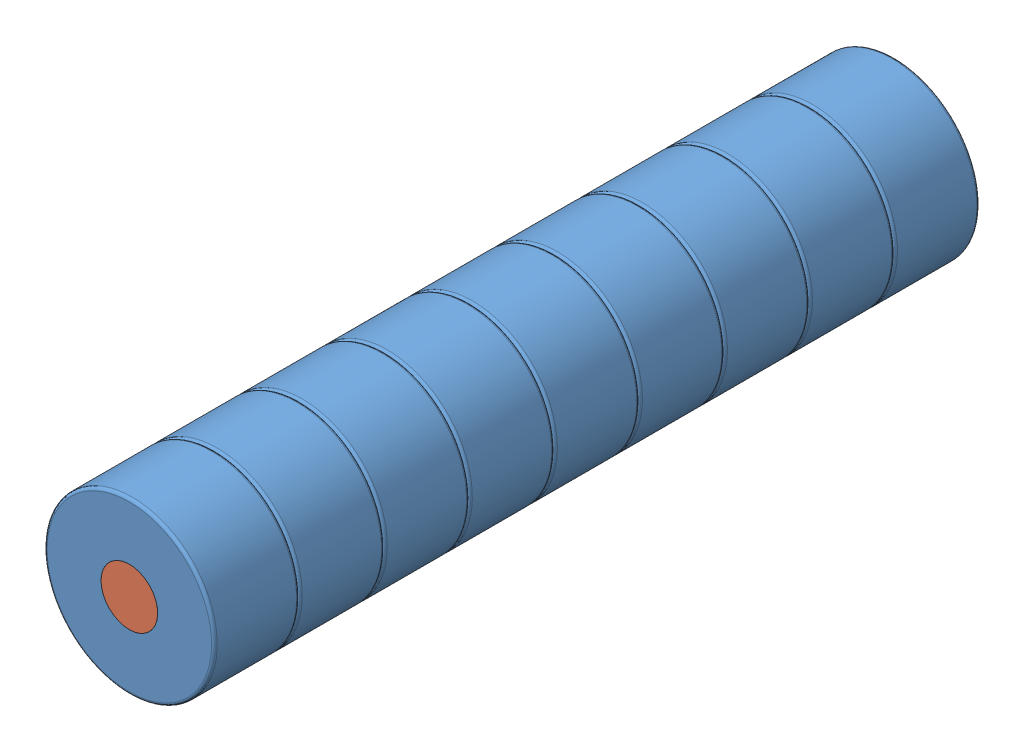
SolidWorks assembly longbearings, configuration Default. Lengths in mm.
Overall size (7.97 7.97 27).
10 component instances, 2 part files, 18 mates.
Components (placement in the parent):
- ballbearing-1: ballbearing [Default] at (2.4595 4.6245 26.9322) x (0 0 1) z (-0.933919 -0.357485 0) size (3 6 6)
- ballbearing-2: ballbearing [Default] at (2.4595 4.6245 2.9322) x (0 0 1) z (-0.999686 0.025064 0) size (3 6 6)
- ballbearing-3: ballbearing [Default] at (2.4595 4.6245 11.9322) x (0 0 1) z (-0.999512 -0.031225 0) size (3 6 6)
- ballbearing-4: ballbearing [Default] at (2.4595 4.6245 23.9322) x (0 0 1) z (-0.99915 -0.041216 0) size (3 6 6)
- ballbearing-5: ballbearing [Default] at (2.4595 4.6245 5.9322) x (0 0 1) z (-0.99915 -0.041216 0) size (3 6 6)
- ballbearing-6: ballbearing [Default] at (2.4595 4.6245 14.9322) x (0 0 1) z (-0.99915 -0.041216 0) size (3 6 6)
- ballbearing-7: ballbearing [Default] at (2.4595 4.6245 8.9322) x (0 0 1) z (-0.99915 -0.041216 0) size (3 6 6)
- ballbearing-8: ballbearing [Default] at (2.4595 4.6245 17.9322) x (0 0 1) z (-0.218913 -0.975744 0) size (3 6 6)
- ballbearing-9: ballbearing [Default] at (2.4595 4.6245 20.9322) x (0 0 1) z (-0.420647 -0.907224 0) size (3 6 6)
- Copy of Copy of Part3^longbearings-1: Copy of Copy of Part3^longbearings [Default] at (-18.2189 -27.0895 2.9322) size (2 2 27) (virtual)
Mates (geometry in assembly coordinates):
- Coincident8: coincident aligned: plane of ballbearing-1 through (2.4595 4.6245 29.9322) normal (0 0 1); plane of Copy of Copy of Part3^Assem1-1 through (2.4595 4.6245 29.9322) normal (0 0 1)
- Concentric3: concentric aligned: cylinder of ballbearing-1 through (2.4595 4.6245 29.9322) axis (0 0 -1) radius 1; cylinder of Copy of Copy of Part3^Assem1-1 through (2.4595 4.6245 29.9322) axis (0 0 -1) radius 1
- Concentric5: concentric aligned: cylinder of ballbearing-3 through (2.4595 4.6245 14.9322) axis (0 0 -1) radius 1; cylinder of Copy of Copy of Part3^Assem1-1 through (2.4595 4.6245 29.9322) axis (0 0 -1) radius 1
- Concentric6: concentric aligned: cylinder of Copy of Copy of Part3^spaced3bearing-1 through (2.4595 4.6245 29.9322) axis (0 0 -1) radius 1; cylinder of ballbearing-4 through (2.4595 4.6245 26.9322) axis (0 0 -1) radius 1
- Coincident9: coincident anti-aligned: plane of ballbearing-1 through (2.4595 4.6245 26.9322) normal (0 0 -1); plane of ballbearing-4 through (2.4595 4.6245 26.9322) normal (0 0 1)
- Concentric7: concentric aligned: cylinder of Copy of Copy of Part3^spaced3bearing-1 through (2.4595 4.6245 29.9322) axis (0 0 -1) radius 1; cylinder of ballbearing-5 through (2.4595 4.6245 8.9322) axis (0 0 -1) radius 1
- Coincident10: coincident anti-aligned: plane of ballbearing-2 through (2.4595 4.6245 5.9322) normal (0 0 1); plane of ballbearing-5 through (2.4595 4.6245 5.9322) normal (0 0 -1)
- Coincident11: coincident aligned: plane of ballbearing-2 through (2.4595 4.6245 2.9322) normal (0 0 -1); plane of Copy of Copy of Part3^spaced3bearing-1 through (2.4595 4.6245 2.9322) normal (0 0 -1)
- Concentric8: concentric aligned: cylinder of ballbearing-2 through (2.4595 4.6245 5.9322) axis (0 0 -1) radius 1; cylinder of Copy of Copy of Part3^spaced3bearing-1 through (2.4595 4.6245 29.9322) axis (0 0 -1) radius 1
- Concentric9: concentric aligned: cylinder of Copy of Copy of Part3^spaced3bearing-1 through (2.4595 4.6245 29.9322) axis (0 0 -1) radius 1; cylinder of ballbearing-6 through (2.4595 4.6245 17.9322) axis (0 0 -1) radius 1
- Coincident12: coincident anti-aligned: plane of ballbearing-3 through (2.4595 4.6245 14.9322) normal (0 0 1); plane of ballbearing-6 through (2.4595 4.6245 14.9322) normal (0 0 -1)
- Concentric10: concentric aligned: cylinder of Copy of Copy of Part3^spaced3bearing-1 through (2.4595 4.6245 29.9322) axis (0 0 -1) radius 1; cylinder of ballbearing-7 through (2.4595 4.6245 11.9322) axis (0 0 -1) radius 1
- Coincident13: coincident anti-aligned: plane of ballbearing-5 through (2.4595 4.6245 8.9322) normal (0 0 1); plane of ballbearing-7 through (2.4595 4.6245 8.9322) normal (0 0 -1)
- Coincident14: coincident anti-aligned: plane of ballbearing-3 through (2.4595 4.6245 11.9322) normal (0 0 -1); plane of ballbearing-7 through (2.4595 4.6245 11.9322) normal (0 0 1)
- Concentric11: concentric aligned: cylinder of Copy of Copy of Part3^spaced3bearing-1 through (2.4595 4.6245 29.9322) axis (0 0 -1) radius 1; cylinder of ballbearing-8 through (2.4595 4.6245 20.9322) axis (0 0 -1) radius 1
- Coincident15: coincident anti-aligned: plane of ballbearing-6 through (2.4595 4.6245 17.9322) normal (0 0 1); plane of ballbearing-8 through (2.4595 4.6245 17.9322) normal (0 0 -1)
- Concentric12: concentric aligned: cylinder of ballbearing-9 through (2.4595 4.6245 23.9322) axis (0 0 -1) radius 1; cylinder of Copy of Copy of Part3^spaced3bearing-1 through (2.4595 4.6245 29.9322) axis (0 0 -1) radius 1
- Coincident16: coincident anti-aligned: plane of ballbearing-4 through (2.4595 4.6245 23.9322) normal (0 0 -1); plane of ballbearing-9 through (2.4595 4.6245 23.9322) normal (0 0 1)
